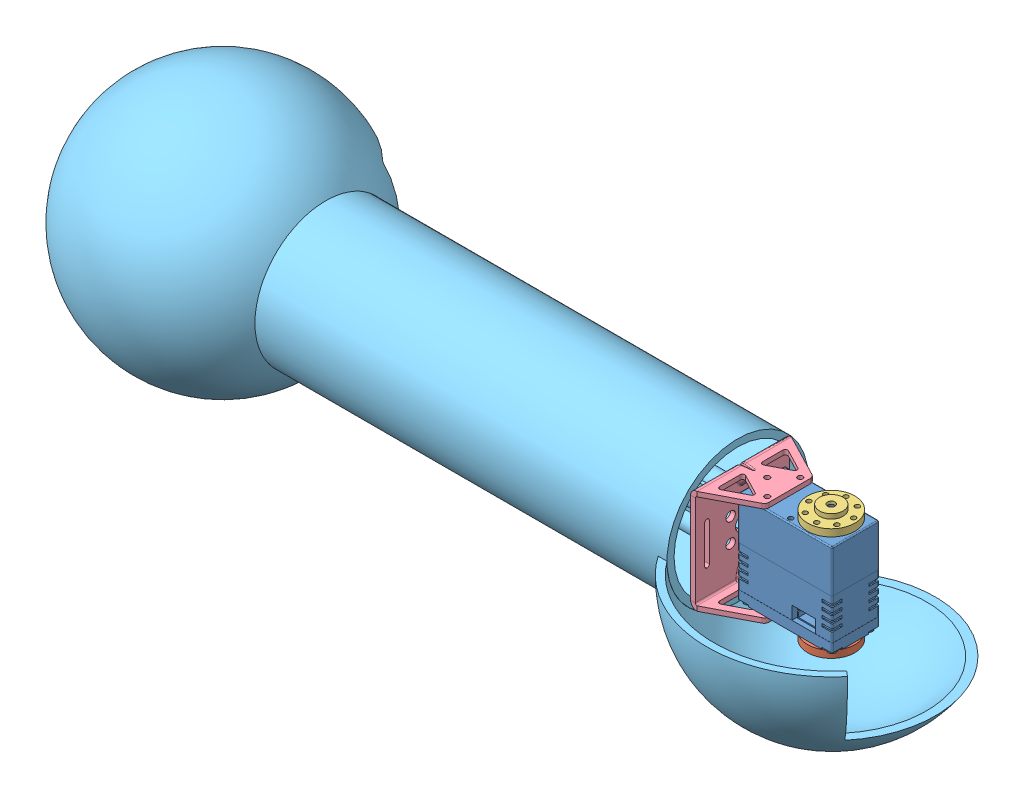
SolidWorks assembly forearm, configuration 默认. Lengths in mm.
Overall size (350.08 106 100.99).
7 component instances, 6 part files, 9 mates.
Components (placement in the parent):
- 舵机-1: 舵机 [默认] at origin size (43.48 52.6 27.66)
  - 舵机-1: 舵机 [默认] at origin size (40 51.4 20)
  - 副舵盘-1: 副舵盘 [默认] at (9.65 -0.8 0) x (-0.933258 0 -0.359207) z (-0.359207 0 0.933258) size (20 5 20)
  - 主舵盘-1: 主舵盘 [默认] at (9.65 40.8 0) x (0.838844 0 0.544372) z (-0.544372 0 0.838844) size (20 5 20)
- 短U支架-1: 短U支架 [默认] at (-28 20 0) x (0 -1 0) z (0 0 1) size (44 22 40)
- 34号舵机连接管-1: 34号舵机连接管 [默认] at (-208.35 20 0) x (0 -1 0) z (0 0 1) size (106 350.08 100.99)
- 大U支架-1: 大U支架 [默认] at (-210.35 20 0) x (0 1 0) z (0 0 1) size (51.6 42 40)
Mates (geometry in assembly coordinates):
- 重合1: coincident anti-aligned: plane of 短U支架-1 through (-28 0 0) normal (0 1 0); plane of 舵机-1/舵机-1 through (0 0 0) normal (0 -1 0)
- 同心1: concentric aligned: circle of 舵机-1/舵机-1; circle of 短U支架-1
- 同心2: concentric aligned: circle of 舵机-1/舵机-1; circle of 短U支架-1
- 重合2: coincident anti-aligned: plane of 短U支架-1 through (-30 20 0) normal (-1 0 0); plane of 120cm连接管-1 through (-30 20 0) normal (1 0 0)
- 重合3: coincident anti-aligned: circle of 短U支架-1; circle of 120cm连接管-1
- 重合4: coincident anti-aligned: circle of 短U支架-1; circle of 120cm连接管-1
- 重合5: coincident anti-aligned: plane of 120cm连接管-1 through (-208.35 20 0) normal (-1 0 0); plane of 大U支架-1 through (-208.35 20 0) normal (1 0 0)
- 同心3: concentric aligned: circle of 120cm连接管-1; circle of 大U支架-1
- 同心4: concentric aligned: circle of 120cm连接管-1; circle of 大U支架-1
